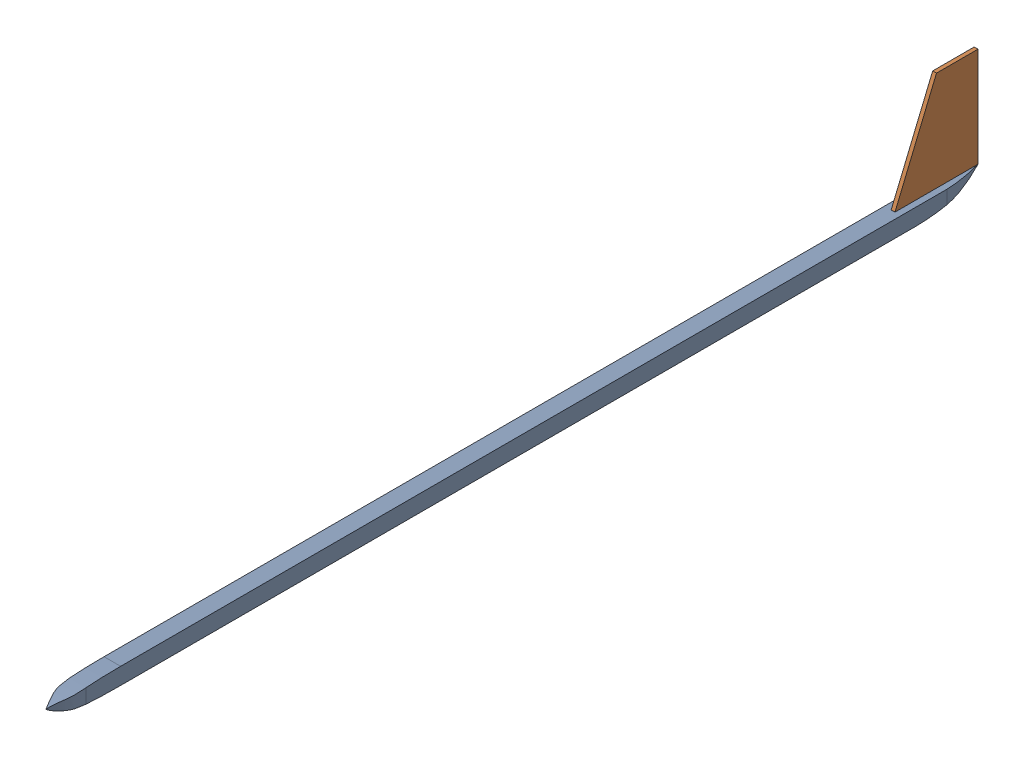
SolidWorks assembly Final Glider Assembly, configuration Default. Lengths in mm.
Overall size (18.66 90.71 711.2).
2 component instances, 2 part files, 3 mates.
Components (placement in the parent):
- PlaneBody-1: PlaneBody [Default] at (-40.7817 26.5412 14.3478) size (18.66 17.01 711.2)
- Tail Fin-1: Tail Fin [Default] at (-42.0517 32.8912 -341.2522) x (0 0 -1) z (0 -1 0) size (63.5 2.92 76.2)
Mates (geometry in assembly coordinates):
- Coincident2: coincident anti-aligned: plane of PlaneBody-1 through (-34.4317 32.8912 -341.2522) normal (0 1 0); plane of Tail Fin-1 through (-38.8767 32.8912 -341.2522) normal (0 -1 0)
- Coincident3: coincident aligned: line of PlaneBody-1 through (-39.1307 32.8912 -341.2522) axis (-1 0 0); line of Tail Fin-1 through (-39.1307 32.8912 -341.2522) axis (-1 0 0)
- Coincident4: coincident: point of PlaneBody-1; point of Tail Fin-1
